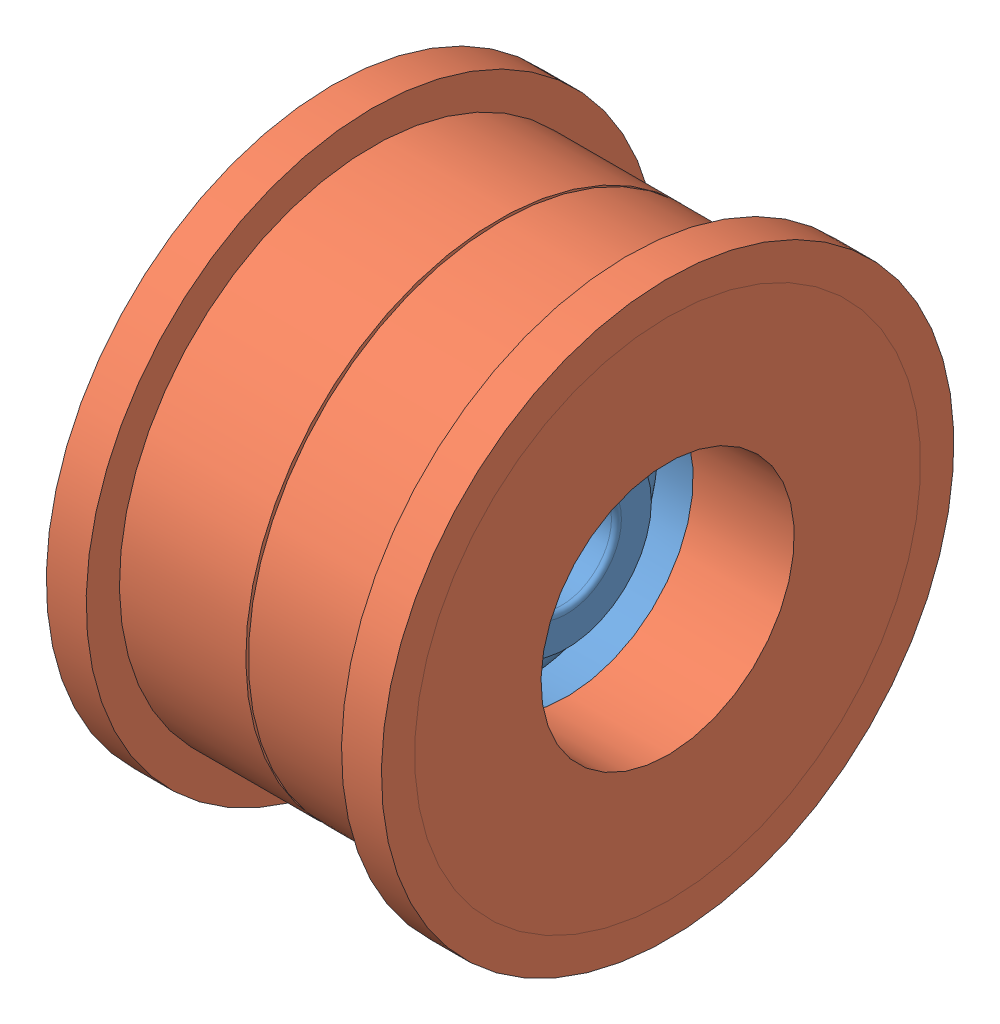
SolidWorks assembly Assembly belt-guide + bearing, configuration Valor predeterminado. Lengths in mm.
Overall size (10.08 24.25 24.25).
3 component instances, 2 part files, 7 mates.
Components (placement in the parent):
- Radial ball bearing DIN 625 - 623-1: Radial ball bearing DIN 625 - 623 [Valor predeterminado] at origin size (4 10 10)
- belt-guide-1: belt-guide [Valor predeterminado] at (5.04 0 0) x (0 -0.638719 0.76944) z (-1 0 0) size (17.22 17.22 5)
- belt-guide-2: belt-guide [Valor predeterminado] at (-5.04 0 0) x (0 -0.984931 0.17295) z (1 0 0) size (17.22 17.22 5)
Mates (geometry in assembly coordinates):
- Concêntrico1: concentric: cylinder of ? through (8.7583 0 0) axis (1 0 0) radius 5; cylinder of ? through (31.3958 0 0) axis (-1 0 0) radius 5.11
- Coincidente1: coincident: plane of ? through (31.3958 4.85 0) normal (1 0 0); plane of ? through (31.3958 0 0) normal (-1 0 0)
- Concêntrico2: concentric: cylinder of ? through (8.7583 0 0) axis (1 0 0) radius 5; cylinder of ? through (27.3958 0 0) axis (1 0 0) radius 5.11
- Coincidente2: coincident: plane of ? through (27.3958 3.95 0) normal (-1 0 0); plane of ? through (27.3958 0 0) normal (1 0 0)
- Coincidente3: coincident: line of ? through (3.7 27.5458 0) axis (0 1 0)
- Coincidente4: coincident: line of ? through (3.7 27.5458 0) axis (0 1 0)
- Simétrico1: symmetric: plane of assembly; plane of assembly; plane of belt-guide-1 through (5.04 0 0) normal (1 0 0); plane of belt-guide-2 through (-5.04 0 0) normal (-1 0 0); plane of assembly
